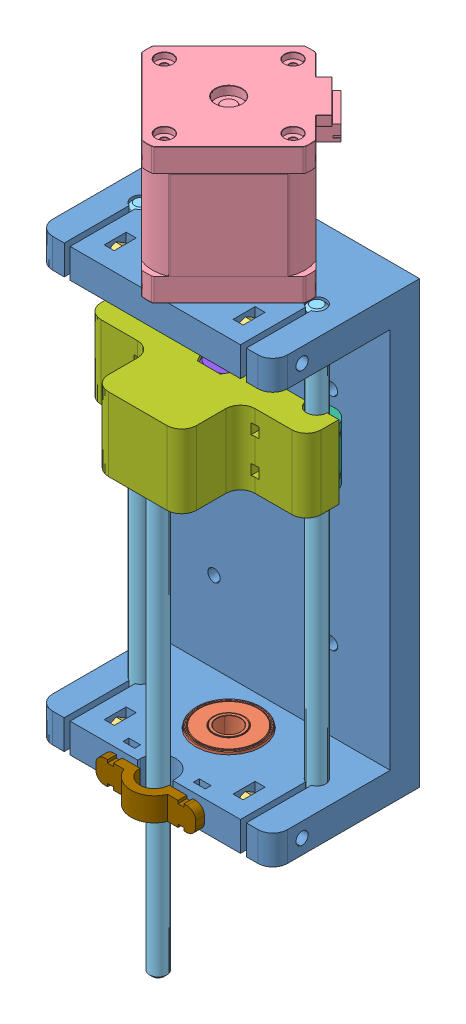
SolidWorks assembly asm3, configuration 預設. Lengths in mm.
Overall size (80 246.64 66.98).
20 component instances, 9 part files, 38 mates.
Components (placement in the parent):
- base_new-1: base_new [預設] at (29.4374 -35.2797 118.4998) size (80 150 50)
- 608zz-1: 608zz [預設] at (29.4374 -102.8797 143.4998) x (0 -1 0) z (0.858976 0 0.512016) size (7 22 22)
- nut_m4-1: nut_m4 [預設] at (53.0805 -105.2797 158.4998) x (0 -1 0) z (-1 0 0) size (8.08 7 3.21)
- nut_m4-2: nut_m4 [預設] at (9.1943 -105.2797 158.4998) x (0 0.5 0.866025) z (-1 0 0) size (8.08 7 3.21)
- Stepper motor-1: Stepper motor [預設] at (29.4374 39.7203 143.4998) x (0.707107 0 0.707107) z (0 1 0) size (42.1 48.05 70.3)
- nut_m4-3: nut_m4 [預設] at (5.7943 34.7203 158.4998) x (0 1 0) z (1 0 0) size (8.08 7 3.21)
- nut_m4-4: nut_m4 [預設] at (49.8805 34.7203 158.4998) x (0 1 0) z (1 0 0) size (8.08 7 3.21)
- 6mm_rod-1: 6mm_rod [預設] at (-0.5626 -110.2797 143.4998) x (1 0 0) z (0 1 0) size (6 6 150)
- 6mm_rod-2: 6mm_rod [預設] at (59.4374 -110.2797 143.4998) x (1 0 0) z (0 1 0) size (6 6 150)
- LM6UU-1: LM6UU [預設] at (59.4374 -12.8154 143.4998) x (-0.812068 0 -0.583563) z (0.583563 0 -0.812068) size (12 19 12)
- LM6UU-2: LM6UU [預設] at (-0.5626 -12.8154 143.4998) x (0.832194 0 0.554485) z (-0.554485 0 0.832194) size (12 19 12)
- base_new2-1: base_new2 [預設] at (29.4374 -3.1154 148.9998) x (1 0 0) z (0 0 -1) size (75 25 40)
- M8-1: M8 [預設] at (29.4374 -8.1154 143.4998) x (0.5 0 -0.866025) z (0 -1 0) size (15.01 13 7.67)
  - M8.step-1: M8.step [預設] at origin size (15.01 13 7.67)
    - ISO4032-M8.step-1: ISO4032-M8.step [預設] at origin size (15.01 13 7.67)
- M8-2: M8 [預設] at (29.4374 8.6846 143.4998) x (0.5 0 -0.866025) z (0 -1 0) size (15.01 13 7.67)
  - M8.step-1: M8.step [預設] at origin size (15.01 13 7.67)
    - ISO4032-M8.step-1: ISO4032-M8.step [預設] at origin size (15.01 13 7.67)
- HOLDER-1: HOLDER [預設] at (29.1826 -106.2797 168.4998) x (1 0 0) z (0 0 -1) size (34 8 8)
- 6mm_rod-3: 6mm_rod [預設] at (29.4374 -10.6154 167.4998) x (0.247177 0 0.96897) z (0 -1 0) size (6 6 150)
Mates (geometry in assembly coordinates):
- 同軸心4: concentric: circle of assembly; circle of assembly; circle of base_new-1; circle of nut_m4-2
- 重合/共線/共點5: coincident: plane of assembly; plane of assembly; plane of base_new-1 through (9.1943 -86.2797 154.7498) normal (-1 0 0); plane of nut_m4-2 through (9.1943 -105.2797 158.4998) normal (1 0 0)
- 平行(R)2: parallel: plane of assembly; plane of assembly; plane of base_new-1 through (9.1943 -86.2797 162.2498) normal (0 0 -1); plane of nut_m4-2 through (9.5143 -107.3004 161.9998) normal (0 0 1)
- 同軸心5: concentric: circle of assembly; circle of assembly; circle of base_new-1; circle of nut_m4-1
- 重合/共線/共點7: coincident: plane of assembly; plane of assembly; plane of base_new-1 through (53.0805 -86.2797 154.7498) normal (-1 0 0); plane of nut_m4-1 through (53.0805 -105.2797 158.4998) normal (1 0 0)
- 平行(R)3: parallel: plane of assembly; plane of assembly; plane of base_new-1 through (49.6805 -86.2797 154.7498) normal (0 0 1); plane of nut_m4-1 through (53.4005 -103.259 154.9998) normal (0 0 -1)
- 同軸心6: concentric: circle of assembly; circle of assembly; circle of base_new-1; circle of 608zz-1
- 重合/共線/共點9: coincident: plane of assembly; plane of assembly; plane of base_new-1 through (29.4374 -106.2797 143.4998) normal (0 1 0); plane of 608zz-1 through (34.5064 -106.2797 134.996) normal (0 -1 0)
- 重合/共線/共點10: coincident: plane of assembly; plane of assembly; plane of base_new-1 through (-10.5626 39.7203 128.4998) normal (0 1 0); plane of Stepper motor-1 through (29.4374 39.7203 143.4998) normal (0 -1 0)
- 同軸心7: concentric: circle of assembly; circle of assembly; circle of base_new-1; circle of Stepper motor-1
- 同軸心8: concentric: circle of assembly; circle of assembly; circle of base_new-1; circle of Stepper motor-1
- 同軸心9: concentric: circle of assembly; circle of assembly; circle of base_new-1; circle of nut_m4-4
- 重合/共線/共點13: coincident: plane of assembly; plane of assembly; plane of base_new-1 through (53.0805 29.7203 154.7498) normal (-1 0 0); plane of nut_m4-4 through (53.0805 34.7203 158.4998) normal (1 0 0)
- 平行(R)4: parallel: plane of assembly; plane of assembly; plane of base_new-1 through (49.6805 29.7203 154.7498) normal (0 0 1); plane of nut_m4-4 through (49.5605 32.6996 154.9998) normal (0 0 -1)
- 同軸心10: concentric: circle of assembly; circle of assembly; circle of base_new-1; circle of nut_m4-3
- 重合/共線/共點15: coincident: plane of assembly; plane of assembly; plane of base_new-1 through (5.7943 29.7203 154.7498) normal (1 0 0); plane of nut_m4-3 through (5.7943 34.7203 158.4998) normal (-1 0 0)
- 平行(R)5: parallel: plane of assembly; plane of assembly; plane of base_new-1 through (5.7943 29.7203 154.7498) normal (0 0 1); plane of nut_m4-3 through (5.4743 32.6996 154.9998) normal (0 0 -1)
- 同軸心11: concentric: circle of assembly; circle of assembly; circle of base_new-1; circle of 6mm_rod-2
- 重合/共線/共點17: coincident: plane of assembly; plane of assembly; plane of base_new-1 through (-10.5626 39.7203 128.4998) normal (0 1 0); plane of 6mm_rod-2 through (59.4374 39.7203 143.4998) normal (0 1 0)
- 同軸心12: concentric: circle of assembly; circle of assembly; circle of base_new-1; circle of 6mm_rod-1
- 重合/共線/共點18: coincident: plane of assembly; plane of assembly; plane of base_new-1 through (-10.5626 39.7203 128.4998) normal (0 1 0); plane of 6mm_rod-1 through (-0.5626 39.7203 143.4998) normal (0 1 0)
- 同軸心13: concentric: cylinder of assembly; cylinder of assembly; cylinder of 6mm_rod-1 through (-0.5626 39.7203 143.4998) axis (0 -1 0) radius 3; cylinder of LM6UU-2 through (-0.5626 -3.3154 143.4998) axis (0 -1 0) radius 3
- 同軸心14: concentric: cylinder of assembly; cylinder of assembly; cylinder of 6mm_rod-2 through (59.4374 39.7203 143.4998) axis (0 -1 0) radius 3; cylinder of LM6UU-1 through (59.4374 -3.3154 143.4998) axis (0 -1 0) radius 3
- 同軸心15: concentric: circle of assembly; circle of assembly; circle of base_new2-1; circle of M8-1/M8.step-1/ISO4032-M8.step-1
- 重合/共線/共點19: coincident: plane of assembly; plane of assembly; plane of base_new2-1 through (29.4374 -8.1154 148.9998) normal (0 -1 0); plane of M8-1/M8.step-1/ISO4032-M8.step-1 through (29.4374 -8.1154 143.4998) normal (0 1 0)
- 同軸心16: concentric: circle of assembly; circle of assembly; circle of base_new2-1; circle of M8-2/M8.step-1/ISO4032-M8.step-1
- 重合/共線/共點20: coincident: plane of assembly; plane of assembly; plane of base_new2-1 through (29.4374 1.8846 148.9998) normal (0 1 0); plane of M8-2/M8.step-1/ISO4032-M8.step-1 through (29.4374 1.8846 143.4998) normal (0 -1 0)
- 平行(R)6: parallel: plane of assembly; plane of assembly; plane of base_new2-1 through (29.4374 -15.6154 136.7498) normal (0 0 1); plane of M8-1/M8.step-1/ISO4032-M8.step-1 through (25.6846 -8.1154 136.9998) normal (0 0 -1)
- 平行(R)7: parallel: plane of assembly; plane of assembly; plane of base_new2-1 through (29.4374 -15.6154 136.7498) normal (0 0 1); plane of M8-2/M8.step-1/ISO4032-M8.step-1 through (25.6846 8.6846 136.9998) normal (0 0 -1)
- 重合/共線/共點23: coincident: circle of assembly; circle of assembly; circle of LM6UU-1; circle of base_new2-1
- 重合/共線/共點24: coincident: plane of assembly; plane of assembly; plane of LM6UU-1 through (57.0012 -12.8154 141.7491) normal (0 -1 0); plane of base_new2-1 through (59.4374 -12.8154 143.4998) normal (0 1 0)
- 同軸心17: concentric: circle of assembly; circle of assembly; circle of LM6UU-2; circle of base_new2-1
- 重合/共線/共點25: coincident: plane of assembly; plane of assembly; plane of LM6UU-2 through (1.934 -12.8154 145.1633) normal (0 -1 0); plane of base_new2-1 through (-0.5626 -12.8154 143.4998) normal (0 1 0)
- 重合/共線/共點26: coincident: plane of assembly; plane of assembly; plane of base_new-1 through (-10.5626 -110.2797 128.4998) normal (0 -1 0); plane of HOLDER-1 through (29.1826 -110.2797 168.4998) normal (0 -1 0)
- 重合/共線/共點27: coincident: plane of assembly; plane of assembly; plane of base_new-1 through (29.4374 -100.2797 168.4998) normal (0 0 1); plane of HOLDER-1 through (24.1826 -110.2797 168.4998) normal (0 0 -1)
- 同軸心18: concentric: cylinder of assembly; cylinder of assembly; cylinder of base_new2-1 through (29.4374 -10.6154 167.4998) axis (0 -1 0) radius 3; cylinder of 6mm_rod-3 through (29.4374 -160.6154 167.4998) axis (0 1 0) radius 3
- 重合/共線/共點28: coincident: plane of assembly; plane of assembly; plane of base_new2-1 through (29.4374 -10.6154 167.4998) normal (0 -1 0); plane of 6mm_rod-3 through (29.4374 -10.6154 167.4998) normal (0 1 0)
- 限制距離1: limit distance = 20.3357 mm: plane of assembly; plane of assembly; plane of base_new2-1 through (29.4374 9.3846 148.9998) normal (0 1 0); plane of base_new-1 through (29.4374 29.7203 118.4998) normal (0 -1 0)
